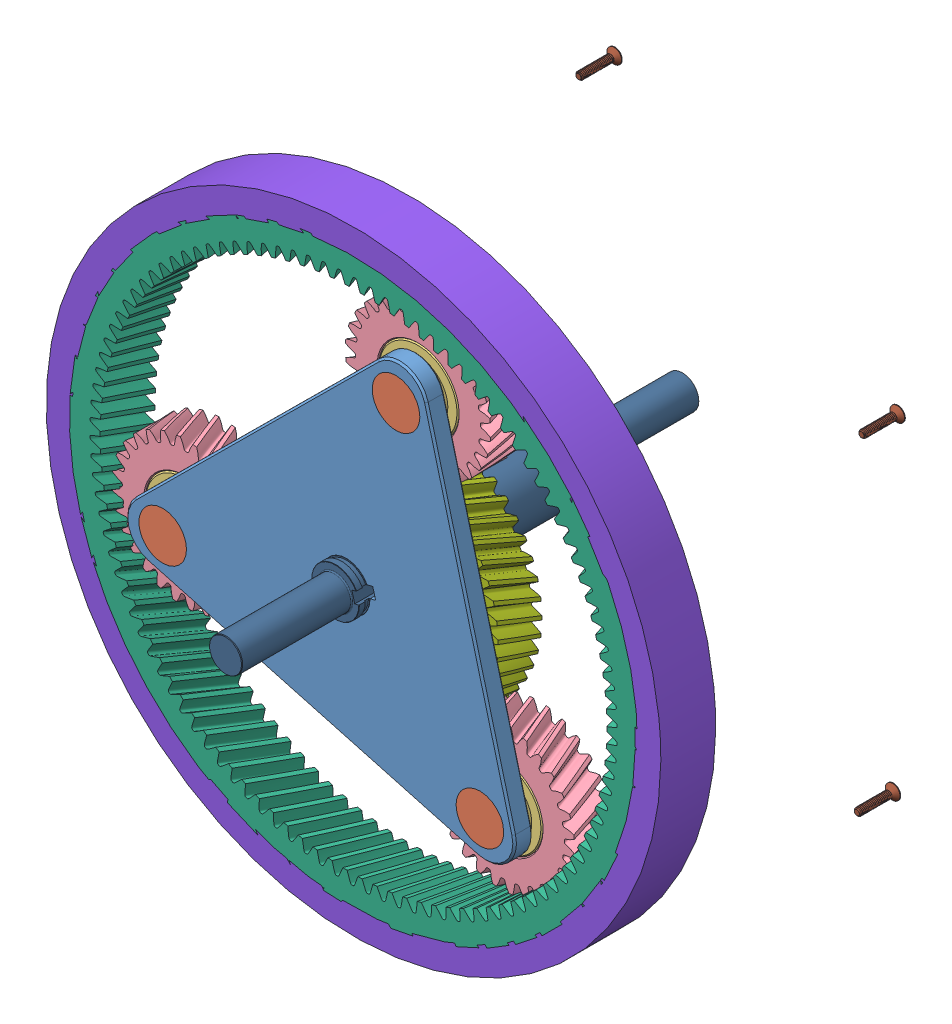
SolidWorks assembly Complete_Assem, configuration Default. Lengths in mm.
Overall size (216.24 216.24 125).
42 component instances, 22 part files, 29 mates.
Components (placement in the parent):
- Planet_Assembly-1: Planet_Assembly [Default] at (-387.7145 -717.5028 80.192) x (-0.255233 0.96688 0) z (0 0 -1) size (141.6 127.61 16) (flexible)
  - Carrier-1: Carrier [Default] at (7.7308 72.6245 98.192) size (109.53 97 5)
  - planetshaftMECH360-1: planetshaftMECH360 [Default] at (-37.1986 98.5645 99.192) x (0.999904 -0.013875 0) z (0 0 1) size (13 13 14.8)
  - planetshaftMECH360-2: planetshaftMECH360 [Default] at (7.7308 20.7445 99.192) x (0.989455 0.144838 0) z (0 0 1) size (13 13 14.8)
  - planetshaftMECH360-4: planetshaftMECH360 [Default] at (52.6602 98.5645 99.192) x (0.962959 0.269649 0) z (0 0 1) size (13 13 14.8)
  - Planet Bearing-10: Planet Bearing [5972K91] at (52.6602 98.5645 102.692) x (0.999904 -0.013875 0) z (0 0 1) size (22 22 7)
  - Planet Bearing-11: Planet Bearing [5972K91] at (7.7308 20.7445 102.692) x (0.989455 0.144838 0) z (0 0 1) size (22 22 7)
  - Planet Bearing-13: Planet Bearing [5972K91] at (-37.1986 98.5645 102.692) x (-0.423247 0.906014 0) z (0 0 1) size (22 22 7)
  - Planet 28t-6: Planet 28t [Planet_Revolving_Follower01] at (52.6602 98.5645 104.192) x (0.773977 0.633214 0) z (0 0 -1) size (40.37 40.37 10)
  - Planet 28t-3: Planet 28t [Planet_Revolving_Follower01] at (-37.1986 98.5645 104.192) x (0.171299 0.985219 0) z (0 0 1) size (40.37 40.37 10)
  - Planet 28t-5: Planet 28t [Planet_Revolving_Follower01] at (7.7308 20.7445 104.192) x (-0.99811 -0.061457 0) z (0 0 -1) size (40.37 40.37 10)
  - 98543A114_SIDE-MOUNT EXTERNAL RETAINING RING  E-STYLE-1: 98543A114_SIDE-MOUNT EXTERNAL RETAINING RING  E-STYLE [98543A114] at (-37.1986 98.5645 106.542) x (0 0 -1) z (0.999904 -0.013875 0) size (0.7 11.8 10.84)
  - 98543A114_SIDE-MOUNT EXTERNAL RETAINING RING  E-STYLE-2: 98543A114_SIDE-MOUNT EXTERNAL RETAINING RING  E-STYLE [98543A114] at (52.6602 98.5645 106.542) x (0 0 -1) z (0.989455 0.144838 0) size (0.7 11.8 10.84)
  - 98543A114_SIDE-MOUNT EXTERNAL RETAINING RING  E-STYLE-4: 98543A114_SIDE-MOUNT EXTERNAL RETAINING RING  E-STYLE [98543A114] at (7.7308 20.7445 106.542) x (0 0 -1) z (0.962959 0.269649 0) size (0.7 11.8 10.84)
- Ring 106t Left Helix-1: Ring 106t Left Helix [Ring_Gear_Fixed01] at (-319.4685 -691.4919 -22.5) x (0.820491 -0.571659 0) z (0 0 -1) size (155.33 155.33 15)
- Sun_Motor_Assembly-1: Sun_Motor_Assembly [Default] at (-450.0979 -693.5412 -257.1332) x (0.250056 -0.968231 0) z (0 0 1) size (168 168 57) (flexible)
  - Motor_assembly_rev1-1: Motor_assembly_rev1 [Default] at (46.357 91.228 140.4438) size (168 168 40) (hidden)
    - Motor_cover_rev1-1: Motor_cover_rev1 [Default] at (-15.6766 35.7639 69.6895) x (0 0 -1) z (1 0 0) size (40 168 168)
    - Motor_stator-1: Motor_stator [Default] at (-15.6766 90.7639 49.6895) x (0 0 1) z (-1 0 0) size (20 160 160)
    - Motor_circuit_board-1: Motor_circuit_board [Default] at (-15.6766 35.7639 41.6895) size (80 120 8)
    - Motor_Rotor_rev1-2: Motor_Rotor_rev1 [Default] at (-15.6766 35.7639 49.6895) x (0.939385 -0.342865 0) z (0 0 1) size (108 108 20)
  - Sun Gear Attachment-1: Sun Gear Attachment [Default] at (46.357 91.228 145.4438) size (80.92 80.87 17)
    - Attachment Detail-1: Attachment Detail [Default] at (-15.6766 35.7639 77.1895) size (80 80 10) (hidden)
    - Sun 50t-1: Sun 50t [Sun_Driver01] at (-15.6766 35.7639 85.6895) x (0.184269 0.982876 0) z (0 0 -1) size (69.28 69.34 12)
- Clutch-2: Clutch [Default] at (-319.4685 -691.4919 -30) x (0.998583 0.053215 0) z (0 0 1) size (168 168 15)
- Sun_bearing-1: Sun_bearing [5972K214] at (-319.4685 -691.4919 -24.5) x (-0.243998 0.969776 0) z (0 0 -1) size (26 26 5)
- End Cap-1: End Cap [Default] at (-319.4685 -691.4919 -75) x (0.898795 -0.438369 0) z (0 0 -1) size (192.41 176.91 10) (hidden)
- shaftMECH360-1: shaftMECH360 [Default] at (-319.4685 -691.4919 20) x (0.255233 -0.96688 0) z (0 0 1) size (20 26.19 125)
- Outer_shaft_bearing-1: Outer_shaft_bearing [5972K231] at (-319.4685 -691.4919 -79) x (0.680316 0.732919 0) z (0 0 -1) size (26 26 8) (hidden)
- Hub_bearing_assembly-1: Hub_bearing_assembly [Default] at (-319.4685 -691.4919 -24.4118) x (0.999904 -0.013875 0) z (0 0 1) size (219 219 85) (hidden)
  - Hub-1: Hub [Default] at origin size (219 219 85)
  - Outer_shaft_bearing-1: Outer_shaft_bearing [5972K231] at (0 0 18.4118) x (0.627924 0.778275 0) z (0 0 1) size (26 26 8)
- Key-1: Key [Default] at (-310.5393 -693.5821 -13) x (-0.96688 -0.255233 0) z (0 0 1) size (3 2.8 5) (hidden)
- Retaining Ring-1: Retaining Ring [98543A218] at (-319.4685 -691.4919 -12.4) x (0 0 1) z (-0.843618 0.536943 0) size (1.2 19.7 18.17) (hidden)
- Screws-1: Screws [91294A006] at (-396.8425 -645.377 -85.2) x (-0.243998 0.969776 0) z (0 0 -1) size (4 4 10.24) (hidden)
- Screws-7: Screws [91294A006] at (-398.0922 -735.4423 -85.2) x (-0.961849 0.273579 0) z (0 0 -1) size (4 4 10.24)
- Screws-8: Screws [91294A006] at (-320.7183 -781.5572 -85.2) x (-0.717851 -0.696196 0) z (0 0 -1) size (4 4 10.24)
- Screws-9: Screws [91294A006] at (-242.0946 -737.6069 -85.2) x (0.243998 -0.969776 0) z (0 0 -1) size (4 4 10.24)
- Screws-10: Screws [91294A006] at (-240.8448 -647.5416 -85.2) x (0.961849 -0.273579 0) z (0 0 -1) size (4 4 10.24)
- Screws-11: Screws [91294A006] at (-318.2188 -601.4266 -85.2) x (0.717851 0.696196 0) z (0 0 -1) size (4 4 10.24)
- ShaftSleeve-1: ShaftSleeve [Default] at (-319.4685 -691.4919 -27) size (21 21 8) (hidden)
- Sun_bearing-2: Sun_bearing [5972K214] at (-319.4685 -691.4919 -42.5) size (26 26 5) (hidden)
Mates (geometry in assembly coordinates):
- Coincident2: coincident anti-aligned: plane of Sun_Motor_Assembly-1/Sun Gear Attachment-1/Attachment Detail-1 through (-319.4685 -691.4919 -27) normal (0 0 1); plane of Sun_bearing-1 through (-309.9386 -689.0942 -27) normal (0 0 -1)
- Concentric12: concentric aligned: cylinder of Sun_Motor_Assembly-1/Sun Gear Attachment-1/Sun 50t-1 through (-319.4685 -691.4919 -26) axis (0 0 -1) radius 13; cylinder of Sun_bearing-1 through (-319.4685 -691.4919 -27) axis (0 0 -1) radius 13
- Concentric14: concentric anti-aligned: cylinder of End Cap-1 through (-319.4685 -691.4919 -83) axis (0 0 1) radius 13; cylinder of Outer_shaft_bearing-1 through (-319.4685 -691.4919 -83) axis (0 0 -1) radius 13
- Coincident4: coincident anti-aligned: plane of End Cap-1 through (-319.4685 -691.4919 -83) normal (0 0 1); plane of Outer_shaft_bearing-1 through (-310.2337 -700.0639 -83) normal (0 0 -1)
- Concentric15: concentric anti-aligned: cylinder of Clutch-2 through (-319.4685 -691.4919 -15) axis (0 0 -1) radius 84; cylinder of Hub_bearing_assembly-1/Hub-1 through (-319.4685 -691.4919 9.4853) axis (0 0 1) radius 84.5
- Concentric16: concentric anti-aligned: cylinder of Planet_Assembly-1/Carrier-1 through (-319.4685 -691.4919 -13) axis (0 0 -1) radius 6.5; cylinder of shaftMECH360-1 through (-319.4685 -691.4919 -75) axis (0 0 1) radius 6.5
- Parallel1: parallel aligned: line of Planet_Assembly-1/Carrier-1 through (-312.213 -688.0252 -13) axis (0.255233 -0.96688 0); line of shaftMECH360-1 through (-314.9203 -688.7399 -10) axis (0.255233 -0.96688 0)
- Coincident9: coincident anti-aligned: plane of Planet_Assembly-1/Carrier-1 through (-281.4267 -729.8171 -18) normal (0 0 -1); plane of shaftMECH360-1 through (-319.4685 -691.4919 -18) normal (0 0 1)
- Concentric17: concentric aligned: cylinder of Sun_Motor_Assembly-1/Motor_assembly_rev1-1/Motor_Rotor_rev1-2 through (-319.4685 -691.4919 -67.001) axis (0 0 1) radius 13; cylinder of shaftMECH360-1 through (-319.4685 -691.4919 -75) axis (0 0 1) radius 6.5
- Coincident10: coincident anti-aligned: plane of Sun_bearing-1 through (-310.983 -689.3569 -22) normal (0 0 1); plane of shaftMECH360-1 through (-319.4685 -691.4919 -22) normal (0 0 -1)
- Concentric19: concentric aligned: cylinder of shaftMECH360-1 through (-319.4685 -691.4919 -105) axis (0 0 1) radius 4.5; cylinder of Hub_bearing_assembly-1/Outer_shaft_bearing-1 through (-319.4685 -691.4919 -2) axis (0 0 1) radius 4.5
- Coincident15: coincident anti-aligned: plane of Planet_Assembly-1/Carrier-1 through (-281.4267 -729.8171 -13) normal (0 0 1); plane of Retaining Ring-1 through (-319.4685 -691.4919 -13) normal (0 0 -1)
- Concentric20: concentric anti-aligned: cylinder of shaftMECH360-1 through (-319.4685 -691.4919 20) axis (0 0 1) radius 6.1; cylinder of Retaining Ring-1 through (-319.4685 -691.4919 -11.8) axis (0 0 -1) radius 9.85
- Distance1: distance = 5 mm anti-aligned: plane of Hub_bearing_assembly-1/Hub-1 through (-319.4685 -691.4919 -10) normal (0 0 -1); plane of Clutch-2 through (-319.4685 -691.4919 -15) normal (0 0 1)
- Coincident25: coincident anti-aligned: plane of shaftMECH360-1 through (-314.9203 -688.7399 -25) normal (0.96688 0.255233 0); plane of Key-1 through (-313.4399 -694.3478 -8) normal (-0.96688 -0.255233 0)
- Coincident26: coincident aligned: line of Planet_Assembly-1/Carrier-1 through (-311.4473 -690.9259 -13) axis (-0.96688 -0.255233 0); line of Key-1 through (-311.2539 -690.8748 -13) axis (-0.96688 -0.255233 0)
- Coincident27: coincident anti-aligned: plane of shaftMECH360-1 through (-319.4685 -691.4919 -10) normal (0 0 1); plane of Hub_bearing_assembly-1/Outer_shaft_bearing-1 through (-323.239 -688.3625 -10) normal (0 0 -1)
- Concentric27: concentric anti-aligned: cylinder of shaftMECH360-1 through (-319.4685 -691.4919 -105) axis (0 0 1) radius 4.5; cylinder of Outer_shaft_bearing-1 through (-319.4685 -691.4919 -83) axis (0 0 -1) radius 4.5
- Concentric28: concentric aligned: cylinder of End Cap-1 through (-318.2961 -607 -82) axis (0 0 -1) radius 12; cylinder of Hub_bearing_assembly-1/Hub-1 through (-318.2961 -607 -82) axis (0 0 -1) radius 12
- Coincident30: coincident anti-aligned: plane of shaftMECH360-1 through (-319.4685 -691.4919 -75) normal (0 0 -1); plane of Outer_shaft_bearing-1 through (-315.8772 -694.8255 -75) normal (0 0 1)
- Coincident32: coincident aligned: cone of End Cap-1 through (-396.8425 -645.377 -85) axis (0 0 1); cone of Screws-1 through (-396.8425 -645.377 -84) axis (0 0 1)
- Coincident33: coincident aligned: plane of Hub_bearing_assembly-1/Hub-1 through (-319.4685 -691.4919 0) normal (0 0 1); plane of assembly through (0 0 0) normal (0 0 1)
- Concentric29: concentric aligned: cylinder of shaftMECH360-1 through (-319.4685 -691.4919 -99.0416) axis (0 0 1) radius 8.5; cylinder of ShaftSleeve-1 through (-319.4685 -691.4919 -35) axis (0 0 1) radius 8.5
- Coincident34: coincident anti-aligned: plane of Sun_bearing-1 through (-309.9386 -689.0942 -27) normal (0 0 -1); plane of ShaftSleeve-1 through (-319.4685 -691.4919 -27) normal (0 0 1)
- Concentric30: concentric aligned: cylinder of shaftMECH360-1 through (-319.4685 -691.4919 -99.0416) axis (0 0 1) radius 8.5; cylinder of Sun_bearing-2 through (-319.4685 -691.4919 -40) axis (0 0 1) radius 8.5
- Coincident35: coincident anti-aligned: plane of Sun_Motor_Assembly-1/Motor_assembly_rev1-1/Motor_cover_rev1-1 through (-319.4685 -691.4919 -45) normal (0 0 1); plane of Sun_bearing-2 through (-319.4685 -682.7419 -45) normal (0 0 -1)
- Concentric31: concentric aligned: cylinder of Sun_Motor_Assembly-1/Sun Gear Attachment-1/Sun 50t-1 through (-319.4685 -691.4919 -26) axis (0 0 -1) radius 13; cylinder of Sun_bearing-1 through (-319.4685 -691.4919 -27) axis (0 0 -1) radius 13
- Concentric35: concentric aligned: cylinder of Ring 106t Left Helix-1 through (-319.4685 -691.4919 -22.5) axis (0 0 -1) radius 77.6651; cylinder of Clutch-2 through (-319.4685 -691.4919 -15) axis (0 0 -1) radius 77
- Coincident41: coincident aligned: plane of Ring 106t Left Helix-1 through (-359.0569 -748.3124 -30) normal (0 0 -1); plane of Clutch-2 through (-319.4685 -691.4919 -30) normal (0 0 -1)
